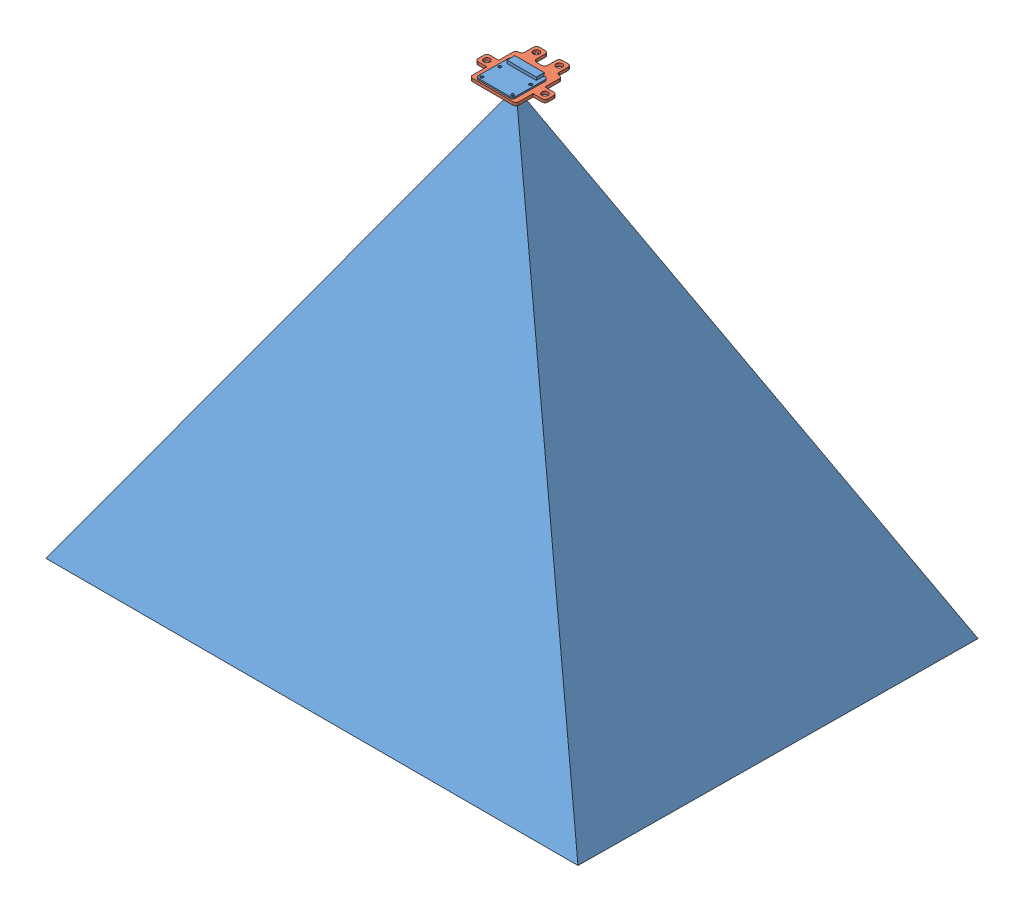
SolidWorks assembly camera_holder, configuration Default. Lengths in mm.
Overall size (47.5 9.21 41.52).
2 component instances, 2 part files, 8 mates.
Components (placement in the parent):
- picamera-1: picamera [Default] at (0 4.8952 -24.0214) x (1 0 0) z (0 -0.008727 -0.999962) size (361.94 309 272.17)
- camera_sled-2: camera_sled [Default] at (0 3.8952 -24.0126) x (1 0 0) z (0 -0.999962 0.008727) size (47.5 41.5 2)
Mates (geometry in assembly coordinates):
- InPlace1: in place: plane of picamera-1 through (0 4.8952 -24.0214) normal (0 0.999962 -0.008727); plane of ? through (0 5.1044 -0.0445) normal (0 0.999962 -0.008727); moOrthogonalPlaneRef_w of picamera-1 through (0 4.8952 -24.0214) normal (0 0.999962 -0.008727); plane of ? through (0 5.1044 -0.0445) normal (0 -0.008727 -0.999962); plane of picamera-1 through (0 4.8952 -24.0214) normal (0 0.999962 -0.008727); plane of ? through (0 5.1044 -0.0445) normal (1 0 0); plane of picamera-1 through (0 4.8952 -24.0214) normal (0 0.999962 -0.008727); unknown of ?
- Coincident1: coincident aligned: plane of picamera-1; plane of ?
- Coincident2: coincident aligned: moOrthogonalPlaneRef_w of picamera-1 through (0 4.8952 -24.0214) normal (0 0.008727 0.999962); plane of camera_sled-1 through (0 4.8952 -24.0214) normal (0 0.008727 0.999962)
- Coincident3: coincident anti-aligned: moOrthogonalPlaneRef_w of picamera-1 through (0 4.8952 -24.0214) normal (1 0 0); plane of camera_sled-1 through (0 4.8952 -24.0214) normal (-1 0 0)
- InPlace2: in place: plane of picamera-1 through (0 3.8952 -24.0126) normal (0 -0.999962 0.008727); plane of ? through (0 4.1045 -0.0358) normal (0 -0.999962 0.008727); plane of picamera-1 through (0 3.8952 -24.0126) normal (0 -0.999962 0.008727); plane of ? through (0 4.1045 -0.0358) normal (0 -0.008727 -0.999962); plane of picamera-1 through (0 3.8952 -24.0126) normal (0 -0.999962 0.008727); plane of ? through (0 4.1045 -0.0358) normal (-1 0 0); plane of picamera-1 through (0 3.8952 -24.0126) normal (0 -0.999962 0.008727); unknown of camera_sled-2
- Coincident4: coincident aligned: plane of picamera-1; plane of camera_sled-2
- Coincident5: coincident aligned: moOrthogonalPlaneRef_w of picamera-1 through (0 3.8952 -24.0126) normal (0 0.008727 0.999962); plane of camera_sled-2 through (0 3.8952 -24.0126) normal (0 0.008727 0.999962)
- Coincident6: coincident anti-aligned: moOrthogonalPlaneRef_w of picamera-1 through (0 3.8952 -24.0126) normal (-1 0 0); plane of camera_sled-2 through (0 3.8952 -24.0126) normal (1 0 0)
